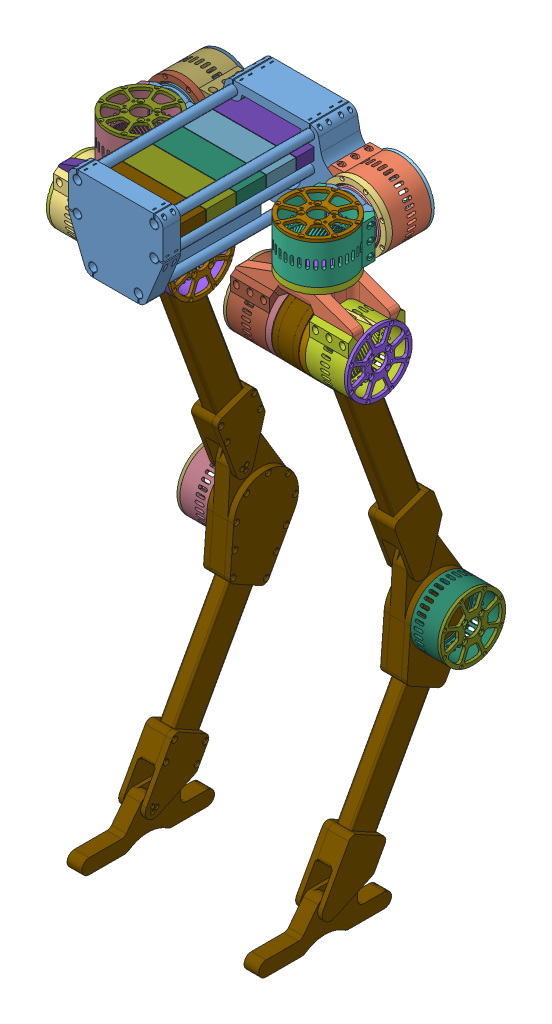
SolidWorks assembly BlackbirdAssembly, configuration Default. Lengths in mm.
Overall size (510.07 1117.72 437.34).
57 component instances, 55 part files, 0 mates.
Components (placement in the parent):
- BlackbirdAssembly.step-1: BlackbirdAssembly.step [Default] at origin size (510.07 1117.72 437.34)
  - Hip Bracket v23.step-1: Hip Bracket v23.step [Default] at (150 0 3.5) size (410.02 110.01 197.54)
    - Component1.step-1: Component1.step [Default] at origin size (380 80.02 43.03)
    - Hip Bracket v23-0.step-1: Hip Bracket v23-0.step [Default] at origin size (110.02 110 66)
    - Hip Bracket v23-1.step-1: Hip Bracket v23-1.step [Default] at origin size (110 110 10.53)
    - Hip Bracket v23-2.step-1: Hip Bracket v23-2.step [Default] at origin size (85.5 85.5 11.5)
    - Hip Bracket v23-3.step-1: Hip Bracket v23-3.step [Default] at origin size (110 110 5.03)
    - Hip Bracket v23-4.step-1: Hip Bracket v23-4.step [Default] at origin size (110 66 110.02)
    - Hip Bracket v23-5.step-1: Hip Bracket v23-5.step [Default] at origin size (110 10.53 110)
    - Hip Bracket v23-6.step-1: Hip Bracket v23-6.step [Default] at origin size (85.5 11.5 85.5)
    - Hip Bracket v23-7.step-1: Hip Bracket v23-7.step [Default] at origin size (110 5.03 110)
    - Hip Bracket v23-8.step-1: Hip Bracket v23-8.step [Default] at origin size (110 110 5.03)
    - Hip Bracket v23-9.step-1: Hip Bracket v23-9.step [Default] at origin size (110 110 10.53)
    - Hip Bracket v23-10.step-1: Hip Bracket v23-10.step [Default] at origin size (110.02 110.01 66)
    - Hip Bracket v23-11.step-1: Hip Bracket v23-11.step [Default] at origin size (110.01 66 110.02)
    - Hip Bracket v23-12.step-1: Hip Bracket v23-12.step [Default] at origin size (85.5 85.5 11.5)
    - Hip Bracket v23-13.step-1: Hip Bracket v23-13.step [Default] at origin size (85.5 11.5 85.5)
    - Hip Bracket v23-14.step-1: Hip Bracket v23-14.step [Default] at origin size (110 5.03 110)
    - Hip Bracket v23-15.step-1: Hip Bracket v23-15.step [Default] at origin size (110 10.53 110)
  - Leg v2 v25.step-1: Leg v2 v25.step [Default] at (150 -129.5 137.5) size (345 953.22 357.33)
  - Base Link.step-1: Base Link.step [Default] at (0 0 66) size (211.04 145 330)
  - Assembly Mockup.step-1: Assembly Mockup.step [Default] at origin size (200 40.52 80)
  - Assembly Mockup-16.step-1: Assembly Mockup-16.step [Default] at origin size (66 110.02 110)
  - Assembly Mockup-17.step-1: Assembly Mockup-17.step [Default] at origin size (5.03 110 110)
  - Assembly Mockup-18.step-1: Assembly Mockup-18.step [Default] at origin size (10.53 110 110)
  - Assembly Mockup-19.step-1: Assembly Mockup-19.step [Default] at origin size (11.5 85.5 85.5)
  - Assembly Mockup-20.step-1: Assembly Mockup-20.step [Default] at origin size (66 110.02 110)
  - Assembly Mockup-21.step-1: Assembly Mockup-21.step [Default] at origin size (5.03 110 110)
  - Assembly Mockup-22.step-1: Assembly Mockup-22.step [Default] at origin size (10.53 110 110)
  - Assembly Mockup-23.step-1: Assembly Mockup-23.step [Default] at origin size (11.5 85.5 85.5)
  - Assembly Mockup-24.step-1: Assembly Mockup-24.step [Default] at origin size (66 110.02 110)
  - Assembly Mockup-25.step-1: Assembly Mockup-25.step [Default] at origin size (5.03 110 110)
  - Assembly Mockup-26.step-1: Assembly Mockup-26.step [Default] at origin size (10.53 110 110)
  - Assembly Mockup-27.step-1: Assembly Mockup-27.step [Default] at origin size (11.5 85.5 85.5)
  - Assembly Mockup-28.step-1: Assembly Mockup-28.step [Default] at origin size (46 110.02 110)
  - Assembly Mockup-29.step-1: Assembly Mockup-29.step [Default] at origin size (5.02 110 110)
  - Assembly Mockup-30.step-1: Assembly Mockup-30.step [Default] at origin size (200 40.52 80)
  - Assembly Mockup-31.step-1: Assembly Mockup-31.step [Default] at origin size (66 110.02 110.01)
  - Assembly Mockup-32.step-1: Assembly Mockup-32.step [Default] at origin size (10.53 110 110)
  - Assembly Mockup-33.step-1: Assembly Mockup-33.step [Default] at origin size (11.5 85.5 85.5)
  - Assembly Mockup-34.step-1: Assembly Mockup-34.step [Default] at origin size (66 110.02 110.01)
  - Assembly Mockup-35.step-1: Assembly Mockup-35.step [Default] at origin size (5.03 110 110)
  - Assembly Mockup-36.step-1: Assembly Mockup-36.step [Default] at origin size (10.53 110 110)
  - Assembly Mockup-37.step-1: Assembly Mockup-37.step [Default] at origin size (11.5 85.5 85.5)
  - Assembly Mockup-38.step-1: Assembly Mockup-38.step [Default] at origin size (5.03 110 110)
  - Assembly Mockup-39.step-1: Assembly Mockup-39.step [Default] at origin size (66 110.02 110.01)
  - Assembly Mockup-40.step-1: Assembly Mockup-40.step [Default] at origin size (5.03 110 110)
  - Assembly Mockup-41.step-1: Assembly Mockup-41.step [Default] at origin size (10.53 110 110)
  - Assembly Mockup-42.step-1: Assembly Mockup-42.step [Default] at origin size (11.5 85.5 85.5)
  - Assembly Mockup-43.step-1: Assembly Mockup-43.step [Default] at origin size (5.02 110 110)
  - Assembly Mockup-44.step-1: Assembly Mockup-44.step [Default] at origin size (46 110.02 110.01)
  - Assembly Mockup-45.step-1: Assembly Mockup-45.step [Default] at origin size (145 20 50)
  - Assembly Mockup-46.step-1: Assembly Mockup-46.step [Default] at origin size (145 20 50)
  - Assembly Mockup-47.step-1: Assembly Mockup-47.step [Default] at origin size (145 20 50)
  - Assembly Mockup-48.step-1: Assembly Mockup-48.step [Default] at origin size (145 20 50)
  - Assembly Mockup-49.step-1: Assembly Mockup-49.step [Default] at origin size (145 20 50)
  - Assembly Mockup-50.step-1: Assembly Mockup-50.step [Default] at origin size (77 70 173)
